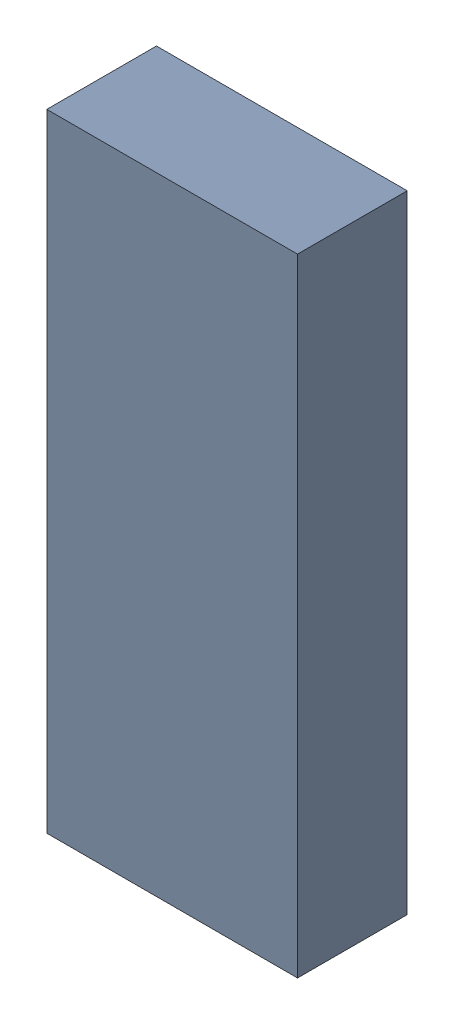
SolidWorks assembly HC1, configuration Default. Lengths in mm.
Overall size (4 10 1.75).
2 component instances, 1 part files, 0 mates.
Components (placement in the parent):
- 1540841040-1: 1540841040 [Default] at (31.75 -26.25 0) size (4 10 1.75)
  - Extruded-1: Extruded [Default] at origin size (4 10 1.75)
